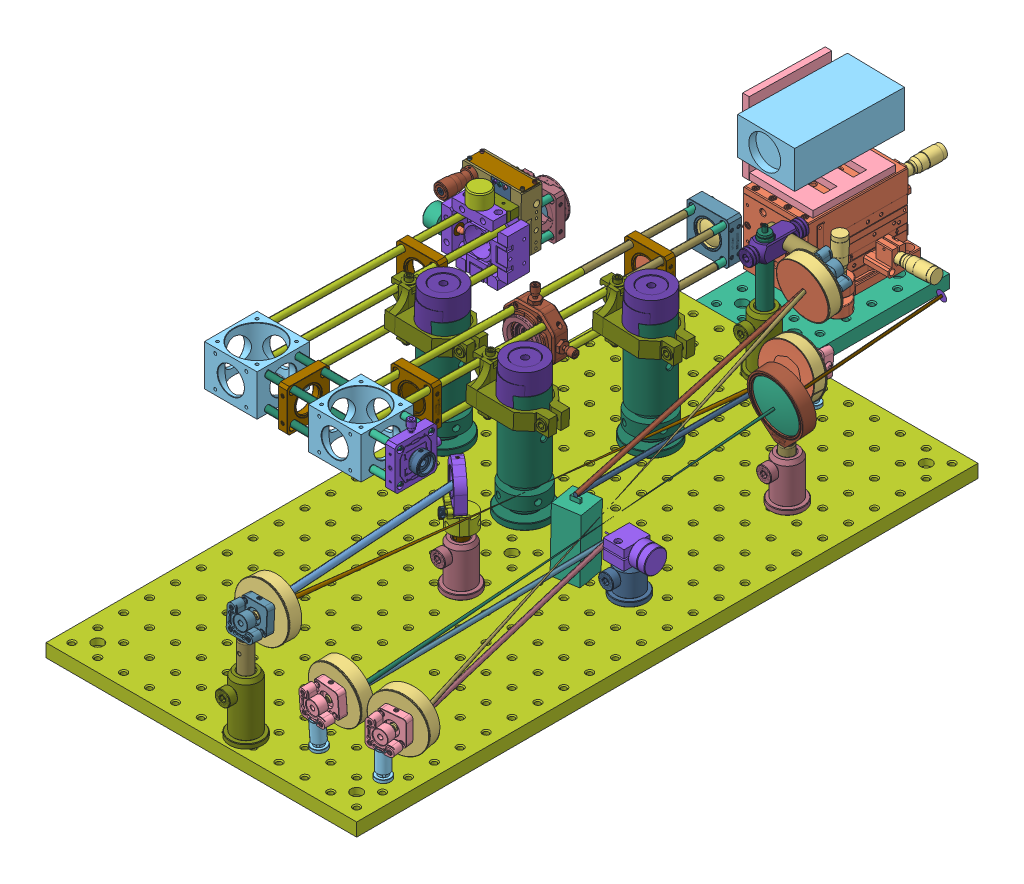
SolidWorks assembly TSLO_Design_10degFOV, configuration Default. Lengths in mm.
Overall size (395.39 174.57 789.72).
210 component instances, 113 part files, 8 mates.
Components (placement in the parent):
- TSLO_Design_10degFOV3-1: TSLO_Design_10degFOV3 [Default] at (0.4999 0.7228 -0.0379) size (50.8 50.73 2.67)
- TSLO_Design_10degFOV4-1: TSLO_Design_10degFOV4 [Default] at (-0.3604 -0.7188 0.0945) size (50.73 50.52 5.94)
- TSLO_Design_10degFOV6-1: TSLO_Design_10degFOV6 [Default] at (-42.4026 0.1036 -3.7055) x (0.984477 -0.039317 0.171053) z (-0.171167 0.000496 0.985242) size (50.19 50.3 10.63)
- TSLO_Design_10degFOV7-1: TSLO_Design_10degFOV7 [Default] at (-1.6852 7.6869 1.0781) size (49.68 50.61 11.51)
- TSLO_Design_10degFOV9-1: TSLO_Design_10degFOV9 [Default] at (1.2315 8.6044 0.1418) size (50.77 50.62 4.63)
- TSLO_Design_10degFOV10-1: TSLO_Design_10degFOV10 [Default] at origin size (50.83 50.58 10.33)
- TSLO_Design_10degFOV11-1: TSLO_Design_10degFOV11 [Default] at (0.6773 1.8275 0.287) size (51.11 51.34 14.75)
- TSLO_Design_10degFOV12-1: TSLO_Design_10degFOV12 [Default] at origin size (9.99 9.91 1.47)
- TSLO_Design_10degFOV13-1: TSLO_Design_10degFOV13 [Default] at origin size (0.01 0.01 0.01)
- TSLO_Design_10degFOV16-1: TSLO_Design_10degFOV16 [Default] at origin size (4.24 56.6 497.81)
- TSLO_Design_10degFOV17-1: TSLO_Design_10degFOV17 [Default] at origin size (28.35 28.26 228.98)
- TSLO_Design_10degFOV18-1: TSLO_Design_10degFOV18 [Default] at origin size (29.55 39.18 247.13)
- TSLO_Design_10degFOV19-1: TSLO_Design_10degFOV19 [Default] at origin size (108.28 74.24 485.17)
- TSLO_Design_10degFOV20-1: TSLO_Design_10degFOV20 [Default] at origin size (56.47 12.3 244.44)
- TSLO_Design_10degFOV21-1: TSLO_Design_10degFOV21 [Default] at origin size (8.14 12.36 250.47)
- TSLO_Design_10degFOV22-1: TSLO_Design_10degFOV22 [Default] at origin size (23.44 57.58 393.39)
- TSLO_Design_10degFOV23-1: TSLO_Design_10degFOV23 [Default] at origin size (2.9 3.59 8.56)
- TSLO_Design_10degFOV24-1: TSLO_Design_10degFOV24 [Default] at origin size (2.76 3.18 5.42)
- TSLO_Design_10degFOV25-1: TSLO_Design_10degFOV25 [Default] at origin size (9.77 22.02 141.62)
- TSLO_Design_10degFOV26-1: TSLO_Design_10degFOV26 [Default] at origin size (2.42 2.43 0.36)
- 2inchmirror_with_inch_post-1: 2inchmirror_with_inch_post [Default] at (61.5861 -55.3257 273.5363) x (0.78082 0.047437 -0.622952) z (0.624718 -0.04837 0.779351) size (63.11 71.72 57.72)
  - 2inchmirror_with_xyz-1: 2inchmirror_with_xyz [Default] at (96.1377 13.1919 -35.348) size (63.11 70.42 57.72)
    - mirror_2inch-1: mirror_2inch [Default] at (-89.1636 -17.1142 13.607) x (0.644317 -0.54211 0.539419) z (0.650262 0.017112 -0.759517) size (50.8 50.8 12)
    - mirror_adapter-1: mirror_adapter [Default] at (-100.2464 -14.5885 18.2612) x (0.650262 0.017112 -0.759517) z (0.739614 0.21417 0.638046) size (19.41 52.32 52.32)
    - U50-P-1: U50-P [Default] at (-95.848 -14.1382 13.466) x (0.733141 -0.025514 0.679598) z (-0.680052 -0.019087 0.732915) size (27.26 27.25 21.55)
  - 1inch_post_thorlabs-1: 1inch_post_thorlabs [Default] at (-7.9317 -30.408 -10.2169) size (14.22 28.05 14.22)
- 2inchmirror_with_inch_post-2: 2inchmirror_with_inch_post [Default] at (119.2581 -54.1791 263.5955) x (0.642788 0 -0.766044) z (0.766044 0 0.642788) size (63.11 71.72 57.72)
  - 2inchmirror_with_xyz-1: 2inchmirror_with_xyz [Default] at (96.1377 13.1919 -35.348) size (63.11 70.42 57.72)
    - mirror_2inch-1: mirror_2inch [Default] at (-89.1636 -17.1142 13.607) x (0.644317 -0.54211 0.539419) z (0.650262 0.017112 -0.759517) size (50.8 50.8 12)
    - mirror_adapter-1: mirror_adapter [Default] at (-100.2464 -14.5885 18.2612) x (0.650262 0.017112 -0.759517) z (0.739614 0.21417 0.638046) size (19.41 52.32 52.32)
    - U50-P-1: U50-P [Default] at (-95.848 -14.1382 13.466) x (0.733141 -0.025514 0.679598) z (-0.680052 -0.019087 0.732915) size (27.26 27.25 21.55)
  - 1inch_post_thorlabs-1: 1inch_post_thorlabs [Default] at (-7.9317 -30.408 -10.2169) size (14.22 28.05 14.22)
- fast_scanner_63.5mm-1: fast_scanner_63.5mm [Default] at (39.3737 -97.6722 22.3123) x (0.165048 0 0.986286) z (-0.017213 -0.999848 0.00288) size (25 25 65.4)
- MB3060M_Aluminum Breadboard_300 mm x 600 mm-1: MB3060M_Aluminum Breadboard_300 mm x 600 mm [Default] at (-174.9824 -107.9238 311.9425) size (300 12.7 600)
- 2inchmirror_with_inch_post-3: 2inchmirror_with_inch_post [Default] at (-16.1312 -54.5357 -257.1868) x (-0.724441 0.054871 0.687149) z (-0.689299 -0.068014 -0.721277) size (63.11 71.72 57.72)
  - 2inchmirror_with_xyz-1: 2inchmirror_with_xyz [Default] at (96.1377 13.1919 -35.348) size (63.11 70.42 57.72)
    - mirror_2inch-1: mirror_2inch [Default] at (-89.1636 -17.1142 13.607) x (0.644317 -0.54211 0.539419) z (0.650262 0.017112 -0.759517) size (50.8 50.8 12)
    - mirror_adapter-1: mirror_adapter [Default] at (-100.2464 -14.5885 18.2612) x (0.650262 0.017112 -0.759517) z (0.739614 0.21417 0.638046) size (19.41 52.32 52.32)
    - U50-P-1: U50-P [Default] at (-95.848 -14.1382 13.466) x (0.733141 -0.025514 0.679598) z (-0.680052 -0.019087 0.732915) size (27.26 27.25 21.55)
  - 1inch_post_thorlabs-1: 1inch_post_thorlabs [Default] at (-7.9317 -30.408 -10.2169) size (14.22 28.05 14.22)
- glavo scanner-1: glavo scanner [Default] at (66.9983 -58.0686 -4.9837) x (0.008727 0.999962 0) z (0 0 1) size (22 46.6 25)
- TR30_M_12.7 mm x 30 mm Stainless Steel Optical Post-1: TR30_M_12.7 mm x 30 mm Stainless Steel Optical Post [Default] at (69.2042 -77.5266 -9.4251) size (12.67 35.33 12.87)
- PH1E - Pedestal Post Holder-1: PH1E - Pedestal Post Holder [Default] at (67.7165 -76.3081 -8.7113) size (31.75 30.71 38.79)
- 2in_lens_mount-1: 2in_lens_mount [Default] at (99.6032 27.4966 -164.0737) x (0.998712 -0.003476 0.050624) z (-0.050624 -0.136587 0.989334) size (55.88 62.36 12.7)
- TR50M_12.7 mm x 50 mm Stainless Steel Optical Post-1: TR50M_12.7 mm x 50 mm Stainless Steel Optical Post [Default] at (69.3327 -65.1804 -161.7866) size (12.67 55.35 12.87)
- PH1.5E - Pedestal Post Holder-1: PH1.5E - Pedestal Post Holder [Default] at (67.6771 -69.4426 -161.28) size (31.75 43.41 38.79)
- 2Inch_mirror_xyz-1: 2Inch_mirror_xyz [Default] at (-13.5145 -11.4462 236.0797) x (0 -0.052336 -0.99863) z (1 -0.000913 0.000048) size (34.71 52.32 52.32)
  - 2in_mirror-1: 2in_mirror [Default] at (-33.2889 4.0201 14.8349) size (19.41 52.32 52.32)
    - mirror_adapter-1: mirror_adapter [Default] at (-17.0311 6.7771 -0.7373) size (19.41 52.32 52.32)
    - mirror_2inch-1: mirror_2inch [Default] at (-6.3517 5.7927 -6.8295) x (0 0 -1) z (1 0 0) size (50.8 50.8 12)
  - newport_U50-P-1: newport_U50-P [Default] at (-44.0753 10.7972 14.0976) x (0 0 1) z (-1 0 0) size (27.26 27.25 21.55)
- 2Inch_mirror_xyz-2: 2Inch_mirror_xyz [Default] at (-13.9776 -12.3598 -217.8966) x (-0.020176 -0.145618 0.989135) z (0.011677 0.989235 0.145871) size (34.71 52.32 52.32)
  - 2in_mirror-1: 2in_mirror [Default] at (-33.2889 4.0201 14.8349) size (19.41 52.32 52.32)
    - mirror_adapter-1: mirror_adapter [Default] at (-17.0311 6.7771 -0.7373) size (19.41 52.32 52.32)
    - mirror_2inch-1: mirror_2inch [Default] at (-6.3517 5.7927 -6.8295) x (0 0 -1) z (1 0 0) size (50.8 50.8 12)
  - newport_U50-P-1: newport_U50-P [Default] at (-44.0753 10.7972 14.0976) x (0 0 1) z (-1 0 0) size (27.26 27.25 21.55)
- TR75_M_12.7 mm x 75 mm Stainless Steel Optical Post-1: TR75_M_12.7 mm x 75 mm Stainless Steel Optical Post [Default] at (-49.7702 -12.7971 -259.7761) size (12.67 80.34 12.87)
- PH2M - Post Holder with Spring_50.8mm_-1: PH2M - Post Holder with Spring_50.8mm_ [Default] at (-52.0198 -62.4796 -258.7303) size (31.75 56.11 38.79)
- TR50M_12.7 mm x 50 mm Stainless Steel Optical Post-2: TR50M_12.7 mm x 50 mm Stainless Steel Optical Post [Default] at (-39.2861 9.7431 -275.7581) x (-0.008727 -0.999962 0) z (0 0 1) size (12.67 55.35 12.87)
- RA90_M-1: RA90_M [Default] at (-51.3925 11.7101 -267.4476) x (0.008727 0 -0.999962) z (-0.008726 0.999962 -0.000076) size (54.16 15.75 15.75)
- TR50M_12.7 mm x 50 mm Stainless Steel Optical Post-3: TR50M_12.7 mm x 50 mm Stainless Steel Optical Post [Default] at (1.5097 -35.6224 292.99) size (12.67 55.35 12.87)
- PH2M - Post Holder with Spring_50.8mm_-2: PH2M - Post Holder with Spring_50.8mm_ [Default] at (-0.5307 -65.6328 293.237) size (31.75 56.11 38.79)
- pmt arm-1: pmt arm [Default] at (-118.5182 -20.1431 -406.0841) size (209.39 76 380.48)
  - pmt arm_monday4-3-1: pmt arm_monday4-3 [Default] at (13.3724 20.5615 327.2828) size (25.4 25.4 3.02)
  - pmt arm_monday5-3-1: pmt arm_monday5-3 [Default] at (15.0015 17.8961 -168.7776) size (25.4 25.4 4)
  - pmt arm_monday6-3-1: pmt arm_monday6-3 [Default] at (12.487 15.4431 -104.7607) size (25.4 25.4 3.02)
  - pmt arm_monday7-3-1: pmt arm_monday7-3 [Default] at (15.7795 18.8269 -264.5344) size (25.4 25.4 4)
  - pmt arm_monday8-3-1: pmt arm_monday8-3 [Default] at (13.4319 22.6372 14.405) size (25.4 25.4 4.67)
  - pmt arm_monday9-3-1: pmt arm_monday9-3 [Default] at origin size (0 0 0.01)
  - C4W - 30 mm Cage System Cube, 4-Way-1: C4W - 30 mm Cage System Cube, 4-Way [Default] at (13.2848 2.1601 483.5578) size (50.8 39.62 50.8)
  - ER1 - Cage Assembly Rod, 1in_Long-4: ER1 - Cage Assembly Rod, 1in_Long [Default] at (48.979 7.9381 470.111) x (0.004689 -0.843391 0.537279) z (0.016086 0.537279 0.843251) size (5.99 30.48 5.99)
  - ER1 - Cage Assembly Rod, 1in_Long-7: ER1 - Cage Assembly Rod, 1in_Long [Default] at (30.0387 2.935 147.6202) x (1 0 0) z (0 0.999848 -0.017452) size (5.99 30.48 5.99)
  - ER1 - Cage Assembly Rod, 1in_Long-8: ER1 - Cage Assembly Rod, 1in_Long [Default] at (28.6821 31.905 150.7575) x (1 0 0) z (0 0.999848 -0.017452) size (5.99 30.48 5.99)
  - ER1 - Cage Assembly Rod, 1in_Long-9: ER1 - Cage Assembly Rod, 1in_Long [Default] at (-1.3881 2.3595 146.237) x (1 0 0) z (0 0.999848 -0.017452) size (5.99 30.48 5.99)
  - ER1 - Cage Assembly Rod, 1in_Long-10: ER1 - Cage Assembly Rod, 1in_Long [Default] at (-0.749 30.8399 146.4204) x (1 0 0) z (0 0.999848 -0.017452) size (5.99 30.48 5.99)
  - ER8-1: ER8 [Default] at (-0.749 34.5475 358.831) x (1 0 0) z (0 0.999848 -0.017452) size (5.99 208.28 5.99)
  - ER1 - Cage Assembly Rod, 1in_Long-11: ER1 - Cage Assembly Rod, 1in_Long [Default] at (49.0132 8.2341 499.933) x (0.004689 -0.843391 0.537279) z (0.016086 0.537279 0.843251) size (5.99 30.48 5.99)
  - ER1 - Cage Assembly Rod, 1in_Long-12: ER1 - Cage Assembly Rod, 1in_Long [Default] at (48.8846 38.1633 499.8888) x (0.004689 -0.843391 0.537279) z (0.016086 0.537279 0.843251) size (5.99 30.48 5.99)
  - ER1 - Cage Assembly Rod, 1in_Long-13: ER1 - Cage Assembly Rod, 1in_Long [Default] at (48.8772 37.9498 469.9111) x (0.004689 -0.843391 0.537279) z (0.016086 0.537279 0.843251) size (5.99 30.48 5.99)
  - Cage XY Flexure Adjustment Plate-1: Cage XY Flexure Adjustment Plate [Default] at (66.031 22.7377 483.4039) x (0 0 1) z (-1 0 0) size (46.58 53.08 8.89)
  - ER8-2: ER8 [Default] at (28.6821 35.6258 363.9194) x (1 0 0) z (0 0.999848 -0.017452) size (5.99 208.28 5.99)
  - ER8-3: ER8 [Default] at (-1.3881 6.068 358.698) x (1 0 0) z (0 0.999848 -0.017452) size (5.99 208.28 5.99)
  - ER8-4: ER8 [Default] at (30.0387 6.6628 361.1873) x (1 0 0) z (0 0.999848 -0.017452) size (5.99 208.28 5.99)
  - CP02_M-1: CP02_M [Default] at (-41.153 20.681 484.4109) x (0.008727 0 -0.999962) z (0.999962 0 0.008727) size (41.4 40.64 8.89)
  - SM05D5D - Ring-Activated SM05 Iris Diaphragm-1: SM05D5D - Ring-Activated SM05 Iris Diaphragm [Default] at (66.4396 13.335 487.0818) x (0 0 1) z (-1 0 0) size (18.41 18.98 12.07)
  - CXY1-1: CXY1 [Default] at (13.6952 19.3801 314.3013) size (64.15 64.15 18.54)
  - ER4-1: ER4 [Default] at (28.6821 32.9867 212.7241) x (1 0 0) z (0 0.999848 -0.017452) size (5.99 106.68 5.99)
  - ER4-2: ER4 [Default] at (28.6821 32.9867 212.7241) x (1 0 0) z (0 0.999848 -0.017452) size (5.99 106.68 5.99)
  - ER4-3: ER4 [Default] at (-1.3881 3.4348 207.845) x (1 0 0) z (0 0.999848 -0.017452) size (5.99 106.68 5.99)
  - ER4-4: ER4 [Default] at (-0.749 31.9144 207.978) x (1 0 0) z (0 0.999848 -0.017452) size (5.99 106.68 5.99)
  - ER4-5: ER4 [Default] at (30.0387 4.0297 210.3343) x (1 0 0) z (0 0.999848 -0.017452) size (5.99 106.68 5.99)
  - CP02_M-2: CP02_M [Default] at (12.487 15.4431 203.835) size (41.4 40.64 8.89)
  - SM1D12C-1: SM1D12C [Default] at (13.6952 19.3801 330.0661) x (-1 0 0) z (0 0 -1) size (35.56 35.56 13.08)
  - CP02T_M-1: CP02T_M [Default] at (14.0234 17.9195 143.1809) size (41.4 40.64 12.71)
  - pmt arm_monday7-3-2: pmt arm_monday7-3 [Default] at (15.7795 18.8269 -264.5344) size (25.4 25.4 4)
  - pmt arm_monday5-3-2: pmt arm_monday5-3 [Default] at (13.9437 15.5461 -107.5045) size (25.4 25.4 4)
  - ER2-1: ER2 [Default] at (-34.7515 38.4742 470.4962) x (0.008727 0.999962 0) z (0 0 1) size (5.99 55.88 5.99)
  - ER2-2: ER2 [Default] at (-35.7437 8.0224 470.0056) x (0.008727 0.999962 0) z (0 0 1) size (5.99 55.88 5.99)
  - ER2-3: ER2 [Default] at (-34.3873 37.8317 499.7231) x (0.008727 0.999962 0) z (0 0 1) size (5.99 55.88 5.99)
  - ER2-4: ER2 [Default] at (-35.2067 9.341 499.8769) x (0.008727 0.999962 0) z (0 0 1) size (5.99 55.88 5.99)
  - C4W - 30 mm Cage System Cube, 4-Way-2: C4W - 30 mm Cage System Cube, 4-Way [Default] at (-87.2234 4.4445 483.4319) size (50.8 39.62 50.8)
  - CP02_M-3: CP02_M [Default] at (13.4298 22.7179 430.3124) size (41.4 40.64 8.89)
  - ER8-5: ER8 [Default] at (-102.4368 37.4178 358.8975) x (1 0 0) z (0 0.999848 -0.017452) size (5.99 208.28 5.99)
  - ER8-6: ER8 [Default] at (-101.3541 8.2543 358.7762) x (1 0 0) z (0 0.999848 -0.017452) size (5.99 208.28 5.99)
  - ER8-7: ER8 [Default] at (-71.809 7.6604 358.4213) x (1 0 0) z (0 0.999848 -0.017452) size (5.99 208.28 5.99)
  - ER8-8: ER8 [Default] at (-70.465 38.5396 358.9784) x (1 0 0) z (0 0.999848 -0.017452) size (5.99 208.28 5.99)
  - CP02_M-4: CP02_M [Default] at (-87.83 21.366 323.4573) size (41.4 40.64 8.89)
  - fiber_coupling-1: fiber_coupling [Default] at (1102.4806 266.1294 -364.4573) size (76 76 84.88)
    - XYVERSCH-1: XYVERSCH [Default] at origin size (76 76 28)
      - 00000605_2-1: 00000605_2 [Default] at origin size (50 50 10)
        - 00000605-1: 00000605 [Default] at origin size (40 10 10)
        - 00000605_1-1: 00000605_1 [Default] at origin size (10 40 10)
      - 00000607_2-1: 00000607_2 [Default] at origin size (49.17 49.17 13)
        - 00000607_3-1: 00000607_3 [Default] at origin size (28.18 13 13)
          - 00000607-1: 00000607 [Default] at origin size (22.68 10 10)
          - 018-1: 018 [Default] at origin size (4.5 13 13)
          - 011-1: 011 [Default] at origin size (12.5 5 5)
        - 00000607_4-1: 00000607_4 [Default] at origin size (13 28.18 13)
          - 00000607_1-1: 00000607_1 [Default] at origin size (10 22.68 10)
          - 018_1-1: 018_1 [Default] at origin size (13 4.5 13)
          - 011_1-1: 011_1 [Default] at origin size (5 12.5 5)
      - KNOPF_2-1: KNOPF_2 [Default] at origin size (56 56 20)
        - KNOPF-1: KNOPF [Default] at origin size (14 20 20)
        - KNOPF_1-1: KNOPF_1 [Default] at origin size (20 14 20)
      - 00000602-1: 00000602 [Default] at origin size (60 60 25)
    - Z_fine_adjustment_M-1: Z_fine_adjustment_M [Default] at (-1248.2166 -56.4584 521.4222) x (1 0 0) z (0 -0.999848 0.017452) size (57 51.51 59.1)
      - 061061_STEP_1-1: 061061_STEP_1 [Default] at origin size (57 51.51 59.1)
        - 000-1: 000 [Default] at origin size (57 51.51 59.1)
          - FEDER-NACHANGEBOTGUTEKUNST-1: FEDER-NACHANGEBOTGUTEKUNST [Default] at origin size (18.5 19.7 22)
            - 00018109-1: 00018109 [Default] at origin size (18.5 0.3 22)
            - 00018109_1-1: 00018109_1 [Default] at origin size (18.5 0.3 22)
          - DIN912-1: DIN912 [Default] at origin size (54 23 23.1)
            - DIN912_1-1: DIN912_1 [Default] at origin size (54 15 6.6)
              - 00010856-1: 00010856 [Default] at origin size (3 3 6.6)
              - 00010856_1-1: 00010856_1 [Default] at origin size (3 3 6.6)
              - 00010856_2-1: 00010856_2 [Default] at origin size (3 3 6.6)
              - 00010856_3-1: 00010856_3 [Default] at origin size (3 3 6.6)
            - DIN912_2-1: DIN912_2 [Default] at origin size (13 6.6 21)
              - 00010856_4-1: 00010856_4 [Default] at origin size (3 6.6 3)
              - 00010856_5-1: 00010856_5 [Default] at origin size (3 6.6 3)
              - 00010856_6-1: 00010856_6 [Default] at origin size (3 6.6 3)
              - 00010856_7-1: 00010856_7 [Default] at origin size (3 6.6 3)
              - 00010856_8-1: 00010856_8 [Default] at origin size (3 6.6 3)
              - 00010856_9-1: 00010856_9 [Default] at origin size (3 6.6 3)
            - DIN912_3-1: DIN912_3 [Default] at origin size (13 6.6 21)
              - 00010856_10-1: 00010856_10 [Default] at origin size (3 6.6 3)
              - 00010856_11-1: 00010856_11 [Default] at origin size (3 6.6 3)
              - 00010856_12-1: 00010856_12 [Default] at origin size (3 6.6 3)
              - 00010856_13-1: 00010856_13 [Default] at origin size (3 6.6 3)
              - 00010856_14-1: 00010856_14 [Default] at origin size (3 6.6 3)
              - 00010856_15-1: 00010856_15 [Default] at origin size (3 6.6 3)
          - 00018111-1: 00018111 [Default] at origin size (55 16 0.5)
          - 00017322-1: 00017322 [Default] at origin size (14 40.14 14)
            - TR-1: TR [Default] at origin size (5.5 9 5.5)
              - 00001130-1: 00001130 [Default] at origin size (5.5 9 5.5)
            - FE-1: FE [Default] at origin size (14 40.14 14)
              - 00020070-1: 00020070 [Default] at origin size (14 40.14 14)
          - 00017862-1: 00017862 [Default] at origin size (57 20 57.5)
    - ER1 - Cage Assembly Rod, 1in_Long-1: ER1 - Cage Assembly Rod, 1in_Long [Default] at (-1204.2984 -257.0495 583.5097) x (1 0 0) z (0 0.999962 -0.008727) size (5.99 30.48 5.99)
    - ER1 - Cage Assembly Rod, 1in_Long-2: ER1 - Cage Assembly Rod, 1in_Long [Default] at (-1173.7185 -227.067 585.1738) x (1 0 0) z (0 0.999962 -0.008727) size (5.99 30.48 5.99)
    - ER1 - Cage Assembly Rod, 1in_Long-3: ER1 - Cage Assembly Rod, 1in_Long [Default] at (-1173.659 -257.6093 585.5459) x (1 0 0) z (0 0.999962 -0.008727) size (5.99 30.48 5.99)
    - ER1 - Cage Assembly Rod, 1in_Long-4: ER1 - Cage Assembly Rod, 1in_Long [Default] at (-1203.7945 -227.8291 585.2812) x (1 0 0) z (0 0.999962 -0.008727) size (5.99 30.48 5.99)
    - CRM1_M-1: CRM1_M [Default] at (-1193.5593 -264.6319 580.3086) x (-0.008727 0 -0.999962) z (0.999962 0 -0.008727) size (15.96 42.67 40.64)
    - SM1FCA-1: SM1FCA [Default] at (-1188.2096 -244.8821 568.4993) x (0.034899 0 0.999391) z (-0.999391 0 0.034899) size (9.11 26.29 26.29)
- post_clamp-1: post_clamp [Default] at (-65.1897 -48.4984 -24.0221) x (0.156434 0 -0.987688) z (0.987688 0 0.156434) size (56.8 128.79 85.13)
  - Adjustable Height 1.5_P-Post-1: Adjustable Height 1.5_P-Post [Default] at (-11.8882 -44.463 36.4807) size (46.99 108.52 46.99)
  - 30 mm Cage Clamp for_1.5Posts-1: 30 mm Cage Clamp for_1.5Posts [Default] at (-0.2499 46.817 -20.9301) x (0.985646 -0.016923 -0.167975) z (0.020899 0.999541 0.021934) size (43.18 77.72 58.17)
  - spacer_post-1: spacer_post [Default] at (5.413 64.341 12.8713) size (37.72 19.99 37.72)
  - spacer_post-2: spacer_post [Default] at (4.4518 53.4901 12.1067) x (0.999782 -0.020899 -0.000229) z (-0.000229 -0.021934 0.999759) size (37.72 19.99 37.72)
- post_clamp-2: post_clamp [Default] at (-65.0835 -48.9592 -146.046) x (0.182236 0 -0.983255) z (0.983255 0 0.182236) size (56.8 128.79 85.13)
  - Adjustable Height 1.5_P-Post-1: Adjustable Height 1.5_P-Post [Default] at (-11.8882 -44.463 36.4807) size (46.99 108.52 46.99)
  - 30 mm Cage Clamp for_1.5Posts-1: 30 mm Cage Clamp for_1.5Posts [Default] at (-0.2499 46.817 -20.9301) x (0.985646 -0.016923 -0.167975) z (0.020899 0.999541 0.021934) size (43.18 77.72 58.17)
  - spacer_post-1: spacer_post [Default] at (5.413 64.341 12.8713) size (37.72 19.99 37.72)
  - spacer_post-2: spacer_post [Default] at (4.4518 53.4901 12.1067) x (0.999782 -0.020899 -0.000229) z (-0.000229 -0.021934 0.999759) size (37.72 19.99 37.72)
- post_clamp-3: post_clamp [Default] at (-163.4102 -45.2434 -43.4551) x (0.165048 0 -0.986286) z (0.986286 0 0.165048) size (56.8 128.79 85.13)
  - Adjustable Height 1.5_P-Post-1: Adjustable Height 1.5_P-Post [Default] at (-11.8882 -44.463 36.4807) size (46.99 108.52 46.99)
  - 30 mm Cage Clamp for_1.5Posts-1: 30 mm Cage Clamp for_1.5Posts [Default] at (-0.2499 46.817 -20.9301) x (0.985646 -0.016923 -0.167975) z (0.020899 0.999541 0.021934) size (43.18 77.72 58.17)
  - spacer_post-1: spacer_post [Default] at (5.413 64.341 12.8713) size (37.72 19.99 37.72)
  - spacer_post-2: spacer_post [Default] at (4.4518 53.4901 12.1067) x (0.999782 -0.020899 -0.000229) z (-0.000229 -0.021934 0.999759) size (37.72 19.99 37.72)
- TR50_M-1: TR50_M [Default] at (11.7697 -79.8356 65.0666) size (12.67 54.97 12.67)
- PH1.5E - Pedestal Post Holder-2: PH1.5E - Pedestal Post Holder [Default] at (-17.4577 -68.1397 68.5644) size (31.75 43.41 38.79)
- 200mm_rod-1: 200mm_rod [Default] at (-13.1255 -1.8011 174.7717) x (-0.233184 0.972364 -0.011529) z (-0.967698 -0.230864 0.101303) size (5.99 208.28 5.99)
- pmt assembly holder-1: pmt assembly holder [Default] at (-86.9419 -24.0258 -401.1532) x (0.008727 0 -0.999962) z (0.999962 0 0.008727) size (162.3 139.71 136.12)
  - xyz_stage_assembly-1: xyz_stage_assembly [Default] at (-24.6069 -31.6205 -20.7618) size (158.4 69.71 136.12)
    - M-562-XYZ-1: M-562-XYZ [Default] at (1.8181 -17.7068 11.0704) size (119.41 69.71 104.71)
    - SM-13-1: SM-13 [Default] at (-17.0509 58.0605 60.826) x (-0.999962 0.008727 0) z (0 0 1) size (12.95 53.72 12.95)
    - SM-13-2: SM-13 [Default] at (2.9599 38.1815 111.1299) x (0.009445 -0.998116 0.060624) z (0.999896 0.008765 -0.011474) size (12.95 53.72 12.95)
    - SM-13-3: SM-13 [Default] at (107.2757 -13.0138 11.4614) x (0.008727 0.999962 0) z (0 0 1) size (12.95 53.72 12.95)
  - cam holder-1: cam holder [Default] at (-15.9364 -42.6038 35.7522) size (79.25 70 69.46)
    - Part5^cam holder-1: Part5^cam holder [Default] at origin (virtual)
    - pmt holder-1: pmt holder [Default] at (-46.4326 62.9836 18.3516) x (-0.008727 0 0.999962) z (-0.999962 0 -0.008727) size (68.77 70 78.65)
  - pmt-1: pmt [Default] at (-0.0539 58.9318 -42.1106) x (0.999962 0 0.008727) z (-0.008727 0 0.999962) size (104.16 36 56.05)
- MB1015M_Aluminum Breadboard_100 mm x 150 mm-1: MB1015M_Aluminum Breadboard_100 mm x 150 mm [Default] at (-147.6969 -108.2151 -283.1771) size (100 12.7 150)
- first flat mirror-1: first flat mirror [Default] at (-90.4613 -48.5861 34.6892) x (-0.788011 0 -0.615661) z (0.615661 0 -0.788011) size (34.34 58 30.2)
  - 9891_flip_mount-1: 9891_flip_mount [Default] at (-78.3223 7.5697 18.8575) size (34.34 58 30.2)
    - 903881-1: 903881 [Default] at origin size (25.68 23.34 25.4)
    - 9891_PLATE-1: 9891_PLATE [Default] at origin size (34.34 56.39 12.77)
      - 903880-1: 903880 [Default] at origin size (34.29 56.39 9.27)
      - 001009-1: 001009 [Default] at origin size (3.51 8.66 3.51)
      - 001014-1: 001014 [Default] at origin size (10.9 13.67 11.05)
      - 001014_1-1: 001014_1 [Default] at origin size (12.03 11.2 12.77)
      - 002380-1: 002380 [Default] at origin size (9.52 1.59 1.59)
      - 002578-1: 002578 [Default] at origin size (2.9 3.2 2.9)
      - 002578_1-1: 002578_1 [Default] at origin size (2.9 3.2 2.9)
    - 002636-1: 002636 [Default] at origin size (2.49 2.49 0.51)
    - 903812_04-1: 903812_04 [Default] at origin size (3.43 3.43 8.25)
    - 903812_03-1: 903812_03 [Default] at origin size (3.45 3.45 14.61)
    - 903279-1: 903279 [Default] at origin size (7.92 7.92 5.72)
    - 903279_1-1: 903279_1 [Default] at origin size (7.92 7.92 5.72)
  - mirror-1: mirror [Default] at (-100.9813 39.8032 24.7878) x (-0.999962 0 -0.008727) z (0.008727 0 -0.999962) size (25.4 25.4 6)
Mates (geometry in assembly coordinates):
- Coincident1: coincident aligned: circle of TSLO_Design_10degFOV9-1; plane of 2inchmirror_with_inch_post-1/2inchmirror_with_xyz-1/mirror_2inch-1 through (48.3567 -54.443 243.3408) normal (0.033136 0.084657 -0.995859)
- Coincident3: coincident: line of fast_scanner_63.5mm-1 through (8.3112 -95.2238 -12.0747) axis (0.165048 0 0.986286); plane of MB3060M_Aluminum Breadboard_300 mm x 600 mm-1 through (-174.9824 -95.2238 -288.0575) normal (0 1 0)
- Concentric1: concentric aligned: circle of TSLO_Design_10degFOV4-1; circle of 2inchmirror_with_inch_post-3/2inchmirror_with_xyz-1/mirror_adapter-1
- Concentric2: concentric anti-aligned: circle of TSLO_Design_10degFOV11-1; circle of 2in_lens_mount-1
- Concentric4: concentric anti-aligned: circle of TSLO_Design_10degFOV3-1; circle of 2Inch_mirror_xyz-1/2in_mirror-1/mirror_2inch-1
- Coincident4: coincident aligned: circle of TSLO_Design_10degFOV6-1; plane of 2Inch_mirror_xyz-2/2in_mirror-1/mirror_2inch-1 through (-2.7334 5.8444 -246.2412) normal (-0.020176 -0.145618 0.989135)
- Coincident8: coincident anti-aligned: plane of MB3060M_Aluminum Breadboard_300 mm x 600 mm-1 through (-174.9824 -95.2238 -288.0575) normal (0 1 0); circle of PH2M - Post Holder with Spring_50.8mm_-2
- Concentric6: concentric anti-aligned: cylinder of TR50_M-1 through (-17.4577 -37.2765 68.5644) axis (0 1 0) radius 6.3373; cylinder of PH1.5E - Pedestal Post Holder-2 through (-17.4577 -49.0897 68.5644) axis (0 -1 0) radius 12.5
